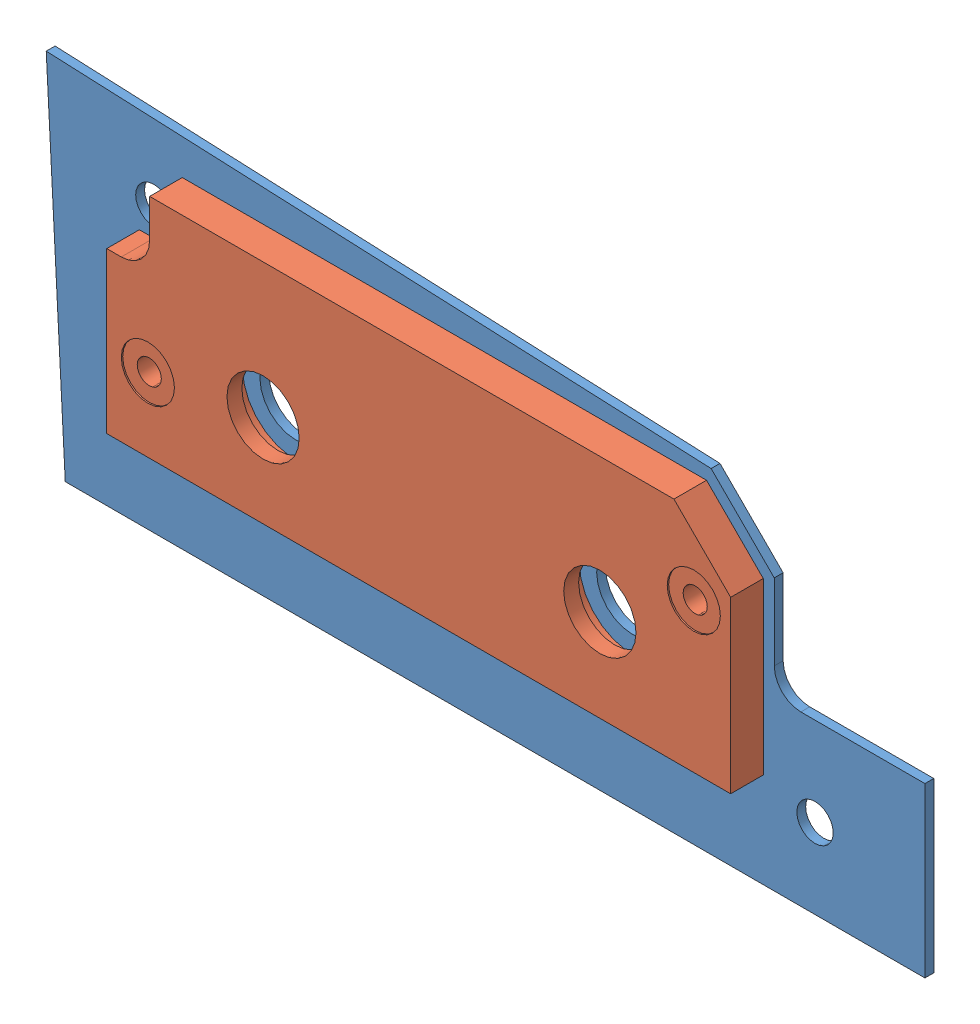
SolidWorks assembly MC HYD ISOL Panel Ref, configuration Default. Lengths in mm.
Overall size (157.4 65.09 7.43).
20 component instances, 9 part files, 0 mates.
Components (placement in the parent):
- MC HYS ISOL Mount Plate Ref-1: MC HYS ISOL Mount Plate Ref [Default] at origin size (157.4 65.09 1.59)
- MC HYS ISOL Light Plate Ref-1: MC HYS ISOL Light Plate Ref [Default] at origin size (111.76 40.64 5.84)
- D5 DZUS Stud Ref v1-1: D5 DZUS Stud Ref v1 [Default] at (-19.685 14.2875 1.5875) size (9.65 9.65 8.83) (hidden)
- D5 DZUS Stud Ref v1-2: D5 DZUS Stud Ref v1 [Default] at (-138.1125 50.8 1.5875) size (9.65 9.65 8.83) (hidden)
- No. 6 Pan Head Phillips Machine Screw Ref v2-1: No. 6 Pan Head Phillips Machine Screw Ref v2 [Default] at (-35.56 43.688 4.0005) size (6.9 6.86 4.05) (hidden)
- No. 6 Pan Head Phillips Machine Screw Ref v2-2: No. 6 Pan Head Phillips Machine Screw Ref v2 [Default] at (-133.35 30.1625 4.0005) size (6.9 6.86 4.05) (hidden)
- MS25081-4 v1-1: MS25081-4 v1 [Default] at (-112.7125 33.528 -1.016) size (18.26 19.09 2.29) (hidden)
- MS25082-8 v2-1: MS25082-8 v2 [Default] at (-112.7125 33.528 -2.0066) size (15.08 16.48 1.98) (hidden)
- MS35333-126 v1-1: MS35333-126 v1 [Default] at (-112.7125 33.528 1.8161) size (15.24 15.24 0.71) (hidden)
- MS25082-8 v2-2: MS25082-8 v2 [Default] at (-112.7125 33.528 3.0353) size (15.08 16.48 1.98) (hidden)
- MS25081-4 v1-2: MS25081-4 v1 [Default] at (-52.3875 33.528 -1.016) size (18.26 19.09 2.29) (hidden)
- MS25082-8 v2-3: MS25082-8 v2 [Default] at (-52.3875 33.528 -2.0066) size (15.08 16.48 1.98) (hidden)
- MS35333-126 v1-2: MS35333-126 v1 [Default] at (-52.3875 33.528 1.8161) size (15.24 15.24 0.71) (hidden)
- MS25082-8 v2-4: MS25082-8 v2 [Default] at (-52.3875 33.528 3.0353) size (15.08 16.48 1.98) (hidden)
- MS Toggle Switch Sealed 3-Position Ref v1-1: MS Toggle Switch Sealed 3-Position Ref v1 [Default] at origin size (14.29 14.29 30.73) (hidden)
  - Toggle Threads Sealed Ref-1: Toggle Threads Sealed Ref [Default] at (41.275 12.7 -6.1811) x (-1 0 0) z (0 0 1) size (14.29 14.29 13.21)
  - Toggle Lever Sealed Ref-1: Toggle Lever Sealed Ref [Default] at (41.275 12.7 -6.1811) x (-1 0 0) z (0 0 1) size (10.67 7.94 27.59)
- MS Toggle Switch Sealed 2-Position Ref v2-1: MS Toggle Switch Sealed 2-Position Ref v2 [Default] at origin size (14.29 17.66 30.89) (hidden)
  - Toggle Threads Sealed Ref-1: Toggle Threads Sealed Ref [Default] at (-25.4 83.058 -5.3811) size (14.29 14.29 13.21)
  - Toggle Lever Sealed Ref-1: Toggle Lever Sealed Ref [Default] at (-25.4 84.7172 -5.1405) x (1 0 0) z (0 -0.284015 0.95882) size (10.67 7.94 27.59)
